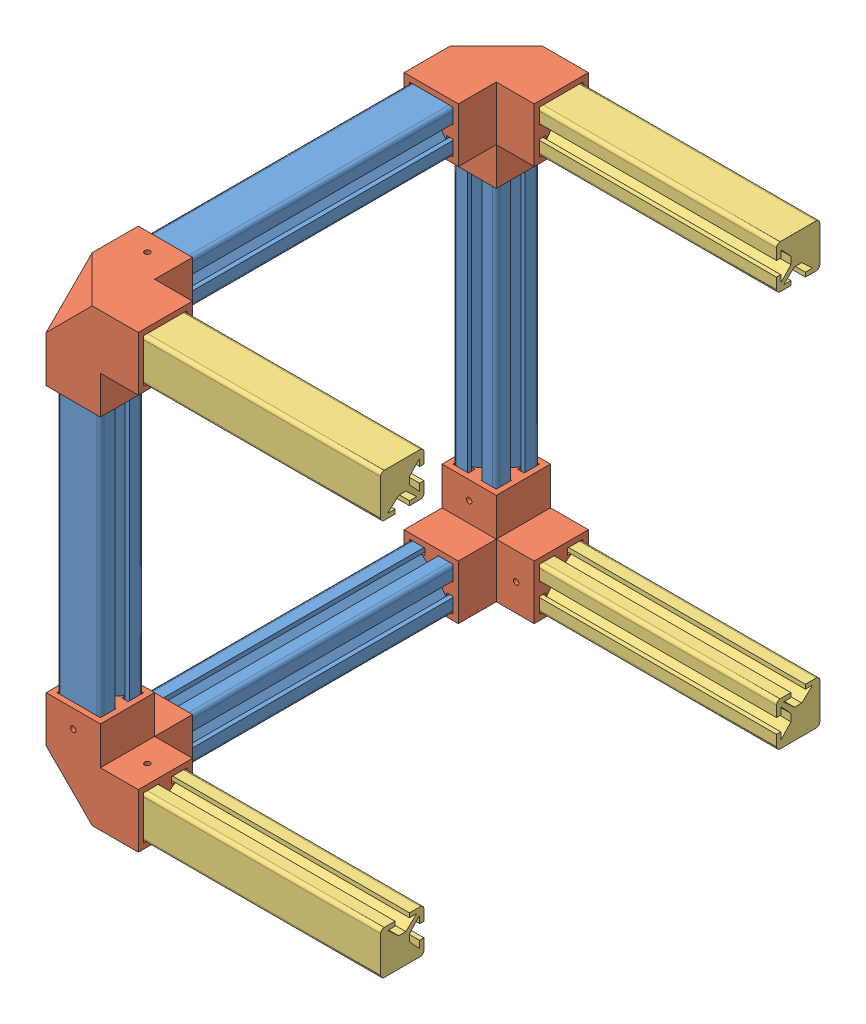
SolidWorks assembly SmallRobotBottomStructure, configuration Défaut. Lengths in mm.
Overall size (91 124.5 124.5).
12 component instances, 3 part files, 33 mates.
Components (placement in the parent):
- BoshProfileABS12x12x96-3faces-5: BoshProfileABS12x12x96-3faces [Défaut] at (-14.7285 1.1739 -6.8094) size (12 12 96)
- ProfileAbsx12x12mmCubeWith3Fix-10: ProfileAbsx12x12mmCubeWith3Fix [Défaut] at (-14.7285 1.1739 47.1906) x (0 1 0) z (-1 0 0) size (25.49 25.49 25.49)
- ProfileAbsx12x12mmCubeWith3Fix-11: ProfileAbsx12x12mmCubeWith3Fix [Défaut] at (-14.7285 1.1739 -62.3094) x (0 0 1) z (-1 0 0) size (25.49 25.49 25.49)
- BoshProfileABS12x12x96-3faces-6: BoshProfileABS12x12x96-3faces [Défaut] at (-14.7285 55.1739 -62.3094) x (1 0 0) z (0 -1 0) size (12 12 96)
- BoshProfileABS12x12x96-3faces-7: BoshProfileABS12x12x96-3faces [Défaut] at (-14.7285 56.6739 47.1906) x (1 0 0) z (0 1 0) size (12 12 96)
- ProfileAbsx12x12mmCubeWith3Fix-12: ProfileAbsx12x12mmCubeWith3Fix [Défaut] at (-14.7285 110.6739 -62.3094) x (0 -1 0) z (-1 0 0) size (25.49 25.49 25.49)
- BoshProfileABS12x12x96-3faces-8: BoshProfileABS12x12x96-3faces [Défaut] at (-14.7285 110.6739 -8.3094) x (1 0 0) z (0 0 -1) size (12 12 96)
- ProfileAbsx12x12mmCubeWith3Fix-13: ProfileAbsx12x12mmCubeWith3Fix [Défaut] at (-14.7285 110.6739 47.1906) x (0 0 -1) z (-1 0 0) size (25.49 25.49 25.49)
- BoshProfileABS12x12x76-2faces-1: BoshProfileABS12x12x76-2faces [Défaut] at (30.7715 1.1739 -62.3094) x (0 1 0) z (1 0 0) size (12 12 76)
- BoshProfileABS12x12x76-2faces-2: BoshProfileABS12x12x76-2faces [Défaut] at (30.7715 110.6739 47.1906) x (0 -1 0) z (1 0 0) size (12 12 76)
- BoshProfileABS12x12x76-2faces-3: BoshProfileABS12x12x76-2faces [Défaut] at (30.7715 1.1739 47.1906) x (0 0 -1) z (1 0 0) size (12 12 76)
- BoshProfileABS12x12x76-2faces-4: BoshProfileABS12x12x76-2faces [Défaut] at (30.7715 110.6739 -62.3094) x (0 0 1) z (1 0 0) size (12 12 76)
Mates (geometry in assembly coordinates):
- Coïncidente2: coincident anti-aligned: plane of BoshProfileABS12x12x96-3faces-5 through (-19.7285 -4.8261 41.1906) normal (0 -1 0); plane of ProfileAbsx12x12mmCubeWith3Fix-10 through (-16.4285 -4.8261 29.2006) normal (0 1 0)
- Coïncidente4: coincident anti-aligned: plane of BoshProfileABS12x12x96-3faces-5 through (-19.7285 -3.8261 41.1906) normal (0 0 1); plane of ProfileAbsx12x12mmCubeWith3Fix-10 through (-20.7285 -4.8261 41.1906) normal (0 0 -1)
- Coïncidente5: coincident anti-aligned: plane of BoshProfileABS12x12x96-3faces-5 through (-20.7285 6.1739 41.1906) normal (-1 0 0); plane of ProfileAbsx12x12mmCubeWith3Fix-10 through (-20.7285 -4.8261 29.2006) normal (1 0 0)
- Coïncidente8: coincident anti-aligned: plane of BoshProfileABS12x12x96-3faces-5 through (-19.7285 -3.8261 -54.8094) normal (0 0 -1); plane of ProfileAbsx12x12mmCubeWith3Fix-11 through (-7.2285 19.1639 -54.8094) normal (0 0 1)
- Coïncidente9: coincident anti-aligned: plane of BoshProfileABS12x12x96-3faces-5 through (-20.7285 6.1739 41.1906) normal (-1 0 0); plane of ProfileAbsx12x12mmCubeWith3Fix-11 through (-20.7285 -0.5261 -44.3194) normal (1 0 0)
- Coïncidente10: coincident anti-aligned: plane of BoshProfileABS12x12x96-3faces-5 through (-19.7285 -4.8261 41.1906) normal (0 -1 0); plane of ProfileAbsx12x12mmCubeWith3Fix-11 through (-20.7285 -4.8261 -44.3194) normal (0 1 0)
- Coïncidente11: coincident anti-aligned: plane of ProfileAbsx12x12mmCubeWith3Fix-11 through (-20.7285 7.1739 -68.3094) normal (0 1 0); plane of BoshProfileABS12x12x96-3faces-6 through (-19.7285 7.1739 -67.3094) normal (0 -1 0)
- Coïncidente12: coincident anti-aligned: plane of ProfileAbsx12x12mmCubeWith3Fix-11 through (-16.4285 19.1639 -68.3094) normal (0 0 1); plane of BoshProfileABS12x12x96-3faces-6 through (-19.7285 7.1739 -68.3094) normal (0 0 -1)
- Coïncidente13: coincident anti-aligned: plane of ProfileAbsx12x12mmCubeWith3Fix-11 through (-8.7285 19.1639 -64.0094) normal (-1 0 0); plane of BoshProfileABS12x12x96-3faces-6 through (-8.7285 7.1739 -57.3094) normal (1 0 0)
- Coïncidente14: coincident anti-aligned: plane of ProfileAbsx12x12mmCubeWith3Fix-10 through (-20.7285 19.1639 53.1906) normal (0 0 -1); plane of BoshProfileABS12x12x96-3faces-7 through (-19.7285 104.6739 53.1906) normal (0 0 1)
- Coïncidente15: coincident anti-aligned: plane of ProfileAbsx12x12mmCubeWith3Fix-10 through (-7.2285 8.6739 29.2006) normal (0 1 0); plane of BoshProfileABS12x12x96-3faces-7 through (-19.7285 8.6739 52.1906) normal (0 -1 0)
- Coïncidente16: coincident anti-aligned: plane of ProfileAbsx12x12mmCubeWith3Fix-10 through (-8.7285 19.1639 53.1906) normal (-1 0 0); plane of BoshProfileABS12x12x96-3faces-7 through (-8.7285 104.6739 42.1906) normal (1 0 0)
- Coïncidente17: coincident anti-aligned: plane of BoshProfileABS12x12x96-3faces-6 through (-19.7285 103.1739 -67.3094) normal (0 1 0); plane of ProfileAbsx12x12mmCubeWith3Fix-12 through (-7.2285 103.1739 -44.3194) normal (0 -1 0)
- Coïncidente18: coincident anti-aligned: plane of BoshProfileABS12x12x96-3faces-6 through (-19.7285 7.1739 -68.3094) normal (0 0 -1); plane of ProfileAbsx12x12mmCubeWith3Fix-12 through (-20.7285 92.6839 -68.3094) normal (0 0 1)
- Coïncidente19: coincident anti-aligned: plane of BoshProfileABS12x12x96-3faces-6 through (-20.7285 7.1739 -57.3094) normal (-1 0 0); plane of ProfileAbsx12x12mmCubeWith3Fix-12 through (-20.7285 92.6839 -56.3094) normal (1 0 0)
- Coïncidente20: coincident anti-aligned: plane of ProfileAbsx12x12mmCubeWith3Fix-12 through (-20.7285 116.6739 -56.3094) normal (0 0 1); plane of BoshProfileABS12x12x96-3faces-8 through (-19.7285 115.6739 -56.3094) normal (0 0 -1)
- Coïncidente21: coincident anti-aligned: plane of ProfileAbsx12x12mmCubeWith3Fix-12 through (-16.4285 116.6739 -44.3194) normal (0 -1 0); plane of BoshProfileABS12x12x96-3faces-8 through (-19.7285 116.6739 -56.3094) normal (0 1 0)
- Coïncidente22: coincident anti-aligned: plane of ProfileAbsx12x12mmCubeWith3Fix-12 through (-8.7285 104.6739 -44.3194) normal (-1 0 0); plane of BoshProfileABS12x12x96-3faces-8 through (-8.7285 105.6739 -56.3094) normal (1 0 0)
- Coïncidente23: coincident anti-aligned: plane of BoshProfileABS12x12x96-3faces-8 through (-19.7285 115.6739 39.6906) normal (0 0 1); plane of ProfileAbsx12x12mmCubeWith3Fix-13 through (-7.2285 92.6839 39.6906) normal (0 0 -1)
- Coïncidente24: coincident anti-aligned: plane of BoshProfileABS12x12x96-3faces-7 through (-20.7285 104.6739 42.1906) normal (-1 0 0); plane of ProfileAbsx12x12mmCubeWith3Fix-13 through (-20.7285 92.6839 45.4906) normal (1 0 0)
- Coïncidente25: coincident anti-aligned: plane of BoshProfileABS12x12x96-3faces-7 through (-19.7285 104.6739 52.1906) normal (0 1 0); plane of ProfileAbsx12x12mmCubeWith3Fix-13 through (-20.7285 104.6739 53.1906) normal (0 -1 0)
- Coïncidente26: coincident: plane of ProfileAbsx12x12mmCubeWith3Fix-11 through (-7.2285 19.1639 -69.8094) normal (1 0 0); plane of BoshProfileABS12x12x76-2faces-1 through (-7.2285 -3.8261 -67.3094) normal (-1 0 0)
- Coïncidente27: coincident: plane of ProfileAbsx12x12mmCubeWith3Fix-11 through (3.2615 -4.8261 -64.0094) normal (0 1 0); plane of BoshProfileABS12x12x76-2faces-1 through (68.7715 -4.8261 -57.3094) normal (0 -1 0)
- Coïncidente28: coincident anti-aligned: plane of ProfileAbsx12x12mmCubeWith3Fix-11 through (3.2615 -4.8261 -68.3094) normal (0 0 1); plane of BoshProfileABS12x12x76-2faces-1 through (68.7715 -3.8261 -68.3094) normal (0 0 -1)
- Coïncidente29: coincident: plane of ProfileAbsx12x12mmCubeWith3Fix-13 through (-7.2285 92.6839 54.6906) normal (1 0 0); plane of BoshProfileABS12x12x76-2faces-2 through (-7.2285 115.6739 52.1906) normal (-1 0 0)
- Coïncidente30: coincident: plane of ProfileAbsx12x12mmCubeWith3Fix-13 through (3.2615 116.6739 53.1906) normal (0 0 -1); plane of BoshProfileABS12x12x76-2faces-2 through (68.7715 115.6739 53.1906) normal (0 0 1)
- Coïncidente31: coincident anti-aligned: plane of ProfileAbsx12x12mmCubeWith3Fix-13 through (3.2615 116.6739 48.8906) normal (0 -1 0); plane of BoshProfileABS12x12x76-2faces-2 through (68.7715 116.6739 42.1906) normal (0 1 0)
- Coïncidente32: coincident: plane of ProfileAbsx12x12mmCubeWith3Fix-10 through (-7.2285 -6.3261 29.2006) normal (1 0 0); plane of BoshProfileABS12x12x76-2faces-3 through (-7.2285 -3.8261 52.1906) normal (-1 0 0)
- Coïncidente33: coincident: plane of ProfileAbsx12x12mmCubeWith3Fix-10 through (3.2615 -4.8261 53.1906) normal (0 1 0); plane of BoshProfileABS12x12x76-2faces-3 through (68.7715 -4.8261 52.1906) normal (0 -1 0)
- Coïncidente34: coincident anti-aligned: plane of ProfileAbsx12x12mmCubeWith3Fix-10 through (3.2615 -0.5261 53.1906) normal (0 0 -1); plane of BoshProfileABS12x12x76-2faces-3 through (68.7715 6.1739 53.1906) normal (0 0 1)
- Coïncidente35: coincident: plane of ProfileAbsx12x12mmCubeWith3Fix-12 through (-7.2285 118.1739 -44.3194) normal (1 0 0); plane of BoshProfileABS12x12x76-2faces-4 through (-7.2285 115.6739 -49.8467) normal (-1 0 0)
- Coïncidente36: coincident: plane of ProfileAbsx12x12mmCubeWith3Fix-12 through (3.2615 116.6739 -68.3094) normal (0 -1 0); plane of BoshProfileABS12x12x76-2faces-4 through (68.7715 116.6739 -49.8467) normal (0 1 0)
- Coïncidente37: coincident anti-aligned: plane of ProfileAbsx12x12mmCubeWith3Fix-12 through (3.2615 112.3739 -68.3094) normal (0 0 1); plane of BoshProfileABS12x12x76-2faces-4 through (68.7715 105.6739 -68.3094) normal (0 0 -1)
